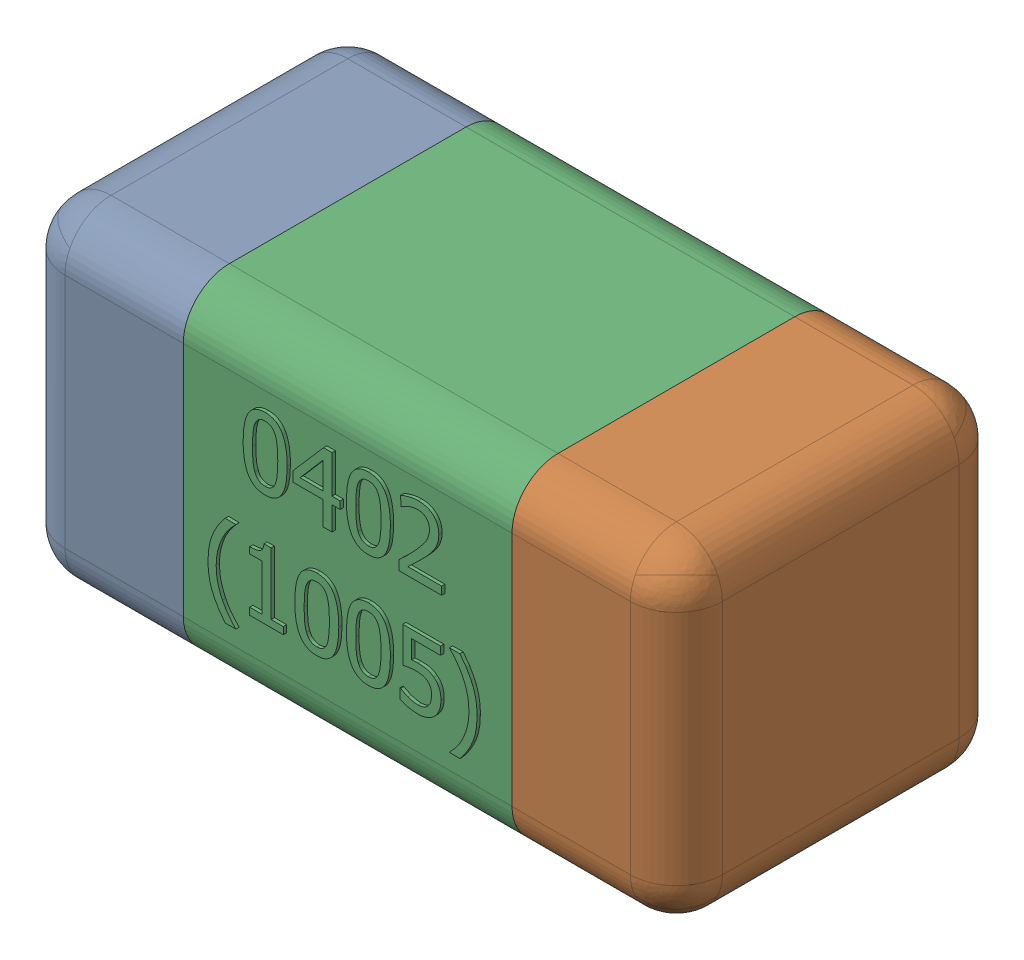
SolidWorks assembly C37, configuration Standard. Lengths in mm.
Overall size (1.01 0.51 0.51).
4 component instances, 3 part files, 0 mates.
Components (placement in the parent):
- C37-subassembly-1-1: C37-subassembly-1 [Standard] at (-11.0999 11.3 0) x (1 0 0) z (0 0 1) size (1.01 0.51 0.51)
  - User Library-0402_Cap-1: User Library-0402_Cap [Standard] at origin size (0.26 0.51 0.51)
  - User Library-0402_Cap-1-1: User Library-0402_Cap-1 [Standard] at origin size (0.26 0.5 0.51)
  - User Library-0402_Cap-2-1: User Library-0402_Cap-2 [Standard] at origin size (0.5 0.5 0.51)
